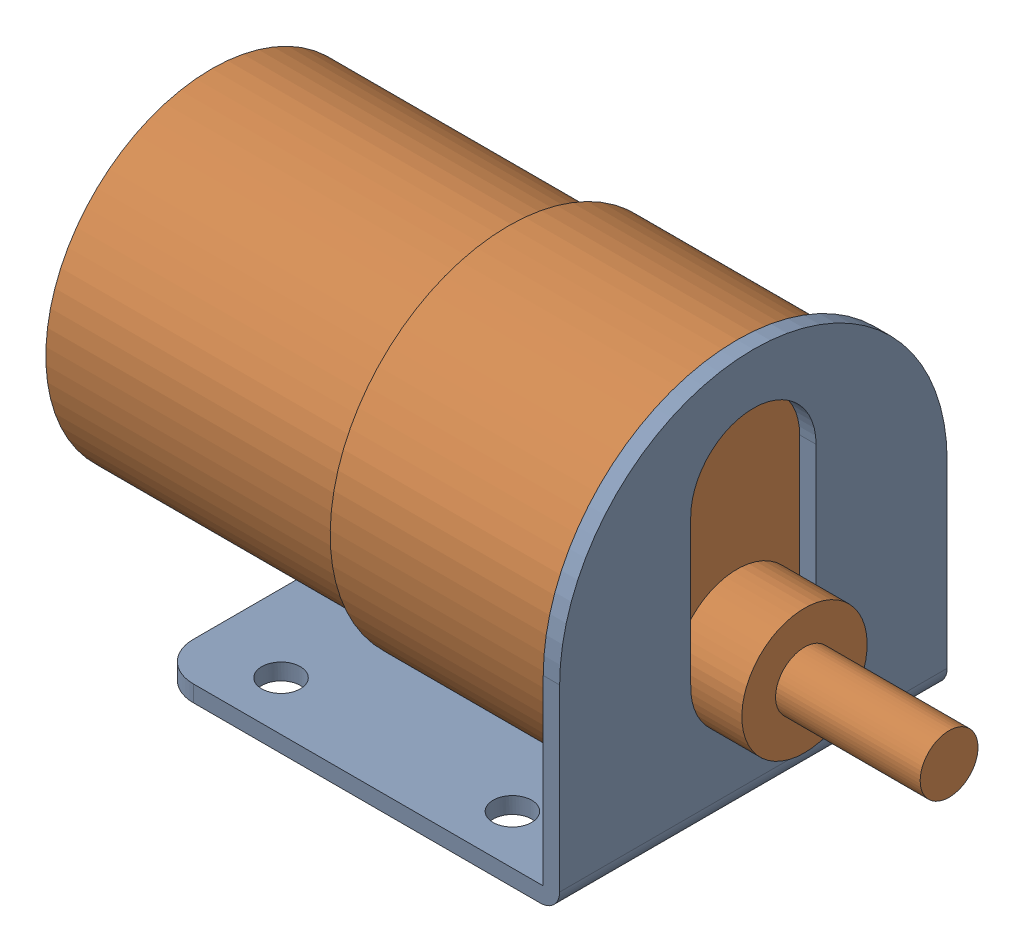
SolidWorks assembly Mirrormoteur+support1, configuration Default. Lengths in mm.
Overall size (79.5 40.7 40.2).
2 component instances, 2 part files, 3 mates.
Components (placement in the parent):
- MirrorsupportMoteur1-1: MirrorsupportMoteur1 [Default] at (46.2429 19.2403 -29.8006) size (42 40.7 40.2)
- MirrormoteurKacem1-1: MirrormoteurKacem1 [Default] at (22.5429 38.1403 -49.9006) x (-1 0 0) z (0 0 -1) size (79.5 37 37)
Mates (geometry in assembly coordinates):
- Coincident1: coincident anti-aligned: plane of MirrorsupportMoteur1-1 through (46.2429 19.2403 -70.0006) normal (-1 0 0); plane of MirrormoteurKacem1-1 through (46.2429 38.1403 -49.9006) normal (1 0 0)
- Concentric1: concentric aligned: cylinder of MirrorsupportMoteur1-1 through (47.9429 38.1403 -49.9006) axis (-1 0 0) radius 20.1; cylinder of MirrormoteurKacem1-1 through (-8.2571 38.1403 -49.9006) axis (-1 0 0) radius 18.5
- Width1: width: plane of MirrorsupportMoteur1-1 through (9.9429 31.3675 -43.4006) normal (0 0 -1); plane of MirrormoteurKacem1-1 through (9.9429 31.3675 -56.4006) normal (0 0 1); cylinder of MirrorsupportMoteur1-1 through (53.2429 31.1403 -49.9006) axis (-1 0 0) radius 6.5
